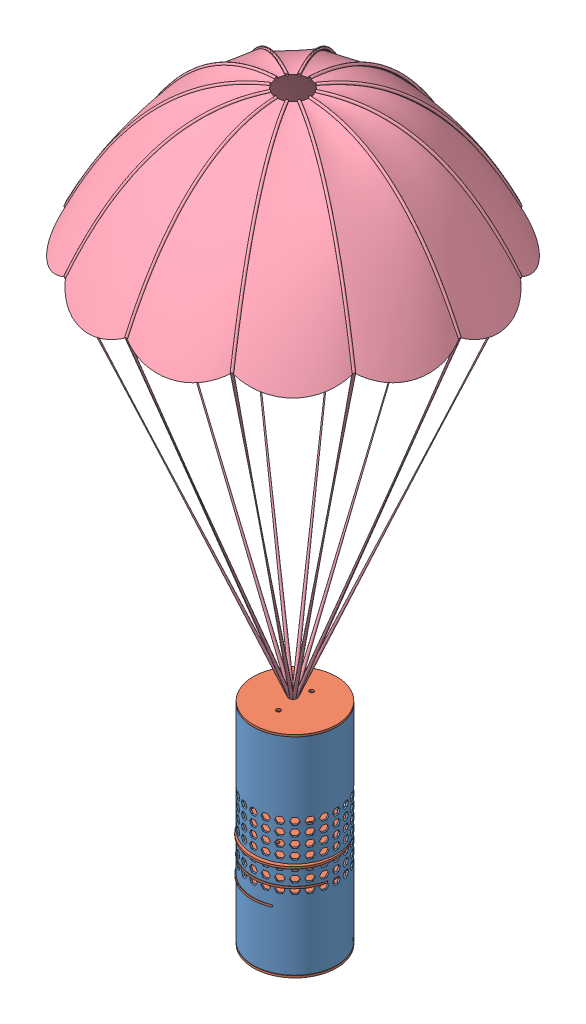
SolidWorks assembly Assem1, configuration Default. Lengths in mm.
Overall size (514.47 1109.73 514.47).
41 component instances, 22 part files, 0 mates.
Components (placement in the parent):
- Hex_cylinder-1: Hex_cylinder [Default] at (91.1529 137.3504 267.5061) size (125 310 125)
- Cap-1: Cap [Default] at (91.1529 292.3504 267.5061) size (125 3 125)
- Sopport_rod-2: Sopport_rod [Default] at (63.4104 -20.4863 219.8871) size (5 310 7.5)
- Sopport_rod-3: Sopport_rod [Default] at (63.7849 -20.4863 315.3414) x (-0.5 0 -0.866025) z (0.866025 0 -0.5) size (5 310 7.5)
- Sopport_rod-4: Sopport_rod [Default] at (146.2634 -20.4863 267.2899) x (-0.5 0 0.866025) z (-0.866025 0 -0.5) size (5 310 7.5)
- Cap-2: Cap [Default] at (89.8415 67.5136 268.0698) size (125 3 125)
- Cap-3: Cap [Default] at (91.0771 95.0935 268.0782) size (125 3 125)
- Cap-4: Cap [Default] at (93.6468 124.0911 272.1304) size (125 3 125)
- Cap-5: Cap [Default] at (91.1529 -21.1493 267.5061) size (125 3 125)
- Teensy_4.0_Assembly-1: Teensy_4.0_Assembly [Default] at (104.901 -19.6782 275.2805) size (36.75 4.12 17.7)
  - Teensy_4.0_PCB-1: Teensy_4.0_PCB [Default] at (-32.9666 11.0804 9.3926) size (35.5 1.4 17.7)
  - Micro USB-B Female 5Pin SMD-1: Micro USB-B Female 5Pin SMD [Default] at (-46.3666 13.7054 9.3926) x (0 0 1) z (0 1 0) size (8.05 5.8 3.73)
  - NXP iMXRT1062-1: NXP iMXRT1062 [Default] at (-33.7166 12.4804 9.3926) x (0 0 1) z (-1 0 0) size (10 1.52 10)
  - SKRPACE010 v4-1: SKRPACE010 v4 [Default] at (-22.5666 12.5304 7.7926) size (4.89 2.55 3.2)
- Adafruit BMP388 Breakout.step-1: Adafruit BMP388 Breakout.step [Default] at (97.3096 -6.5674 258.8641) size (21.59 11.6 16.51)
  - MalePinHeader.step-1: MalePinHeader.step [Default] at (14.8329 -4.1349 22.0117) size (2.54 11.54 2.54)
  - MalePinHeader.step-2: MalePinHeader.step [Default] at (9.7562 -4.1349 22.0162) size (2.54 11.54 2.54)
  - MalePinHeader.step-3: MalePinHeader.step [Default] at (7.2156 -4.1349 21.9989) size (2.54 11.54 2.54)
  - MalePinHeader.step-4: MalePinHeader.step [Default] at (-0.4008 -4.1349 21.997) size (2.54 11.54 2.54)
  - MalePinHeader.step-5: MalePinHeader.step [Default] at (-2.9499 -4.1349 22.0117) size (2.54 11.54 2.54)
  - MalePinHeader.step-6: MalePinHeader.step [Default] at (12.3028 -4.1349 22.0061) size (2.54 11.54 2.54)
  - MalePinHeader.step-7: MalePinHeader.step [Default] at (2.1379 -4.1349 22.0105) size (2.54 11.54 2.54)
  - MalePinHeader.step-8: MalePinHeader.step [Default] at (4.6865 -4.1349 22.0155) size (2.54 11.54 2.54)
  - Bosch BMP388.step-1: Bosch BMP388.step [Default] at (6.2406 0.0201 15.767) size (2 0.75 2)
  - SOD-523F Package.step-1: SOD-523F Package.step [Default] at (9.3077 0.02 14.6929) size (1.6 0.7 0.8)
  - SOT-23-5.step-1: SOT-23-5.step [Default] at (-0.8779 0.02 16.4671) x (0 0 -1) z (1 0 0) size (2.8 1.45 2.9)
  - SOT-363.step-1: SOT-363.step [Default] at (11.8928 0.77 18.7503) size (2.1 1.1 2)
  - 0603 Isolated 4 Resistor Array.step-1: 0603 Isolated 4 Resistor Array.step [Default] at (14.3354 0.02 15.5451) x (0 0 1) z (0 1 0) size (3.2 1.6 0.61)
  - Capacitor 0805 T1.35 BN.step-1: Capacitor 0805 T1.35 BN.step [Default] at (-1.0453 0.695 18.8902) size (2.1 1.35 1.35)
  - Capacitor 0805 T1.35 BN.step-2: Capacitor 0805 T1.35 BN.step [Default] at (1.1606 0.695 16.384) x (0 0 -1) z (1 0 0) size (2.1 1.35 1.35)
  - Capacitor 0603 T0.9 BN.step-1: Capacitor 0603 T0.9 BN.step [Default] at (3.9082 0.47 16.3763) x (0 0 1) z (-1 0 0) size (1.7 0.9 0.9)
  - Resistor 0603.step-1: Resistor 0603.step [Default] at (12.1248 -0.03 14.2385) size (1.7 0.55 0.9)
  - Resistor 0603.step-2: Resistor 0603.step [Default] at (6.6546 -0.03 18.7736) x (0 0 1) z (-1 0 0) size (1.7 0.55 0.9)
  - Adafruit BMP388 Breakout.step-1: Adafruit BMP388 Breakout.step [Default] at origin size (21.59 1.62 16.51)
- Holder-1: Holder [Default] at (132.2974 -7.6514 262.7777) x (0.104528 0.994522 0) z (0 0 1) size (19.6 19.6 65.3)
- battery-1: battery [Default] at (131.9473 -8.2263 229.8604) x (1 0 0) z (0 -0.999962 0.008727) size (18.5 66.3 18.5)
- XBee Pro 60mW-1: XBee Pro 60mW [Default] at (86.3213 -7.1493 251.7928) size (33 30 25)
  - XBee Pro 60mW PCB-1: XBee Pro 60mW PCB [Default] at (-26.8117 -5.3484 14.4414) size (33 25 25)
  - 10x Pinheader Male-1: 10x Pinheader Male [Default] at (-19.6678 -5.3484 -9.4947) x (0 0 -1) z (-1 0 0) size (2 9 20)
  - 10x Pinheader Male-2: 10x Pinheader Male [Default] at (-19.6678 -5.3484 13.3775) x (0 0 -1) z (-1 0 0) size (2 9 20)
- Para_2-1: Para_2 [Default] at (83.8595 886.5821 263.169) size (514.47 802 514.47)
